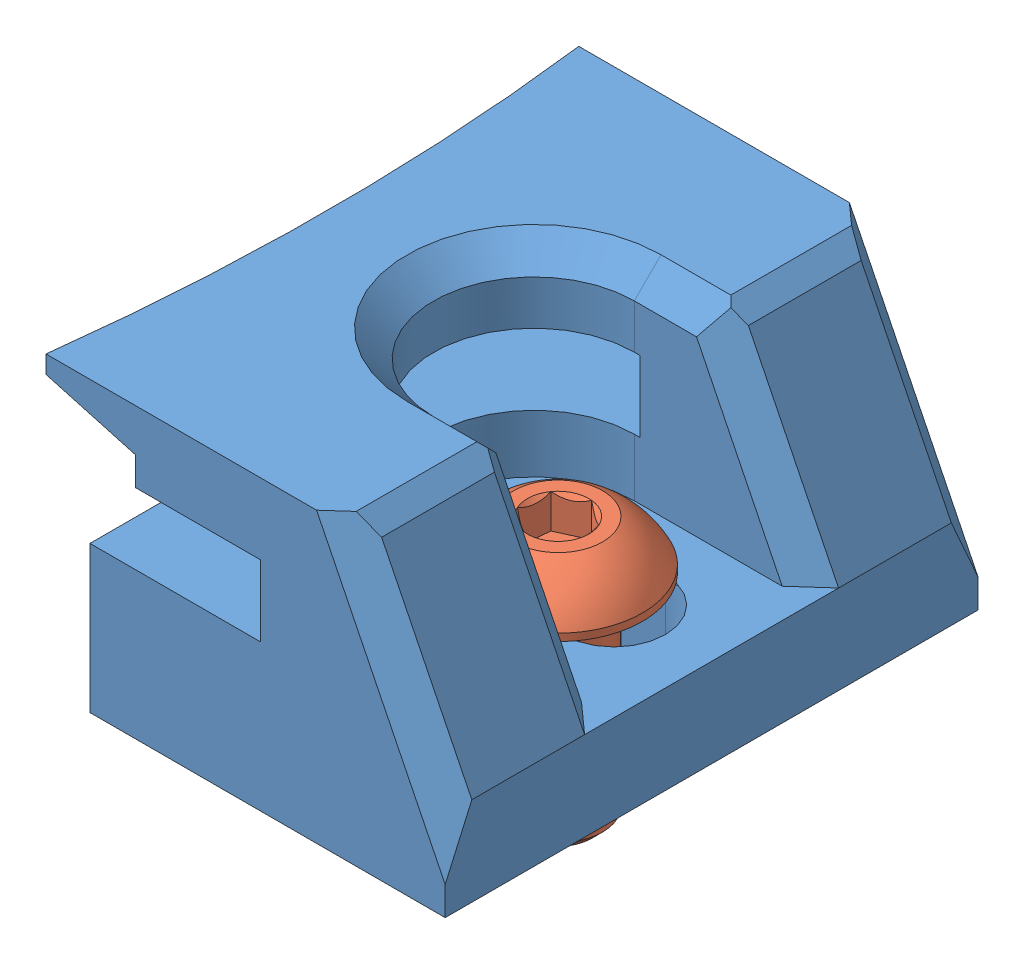
SolidWorks assembly Heated Bed Glass Clamps, configuration Default. Lengths in mm.
Overall size (22.48 23.25 30).
3 component instances, 3 part files, 8 mates.
Components (placement in the parent):
- Glass_clamp-1: Glass_clamp [Default] at origin size (22.48 16.25 30)
- M5 x 12mm -  Button Head Screw - SST (92095A210)-1: M5 x 12mm -  Button Head Screw - SST (92095A210) [92095A210] at (11.359 7.75 0) x (0.413548 0 0.910482) z (0 1 0) size (9.5 9.5 14.92)
- Tee Nut-1: Tee Nut [Default] at (11.359 -1.8 0) x (0 0 -1) z (0 -1 0) size (15 10 3)
Mates (geometry in assembly coordinates):
- Coincident1: coincident aligned: plane of Glass_clamp-1 through (0 0 0) normal (0 0 1); plane of assembly through (0 0 0) normal (0 0 1)
- Coincident2: coincident aligned: plane of Glass_clamp-1 through (0 0 0) normal (0 1 0); plane of assembly through (0 0 0) normal (0 1 0)
- Coincident3: coincident aligned: plane of Glass_clamp-1 through (0 0 0) normal (1 0 0); plane of assembly through (0 0 0) normal (1 0 0)
- Slot1: slot anti-aligned: cylinder of M5 x 12mm -  Button Head Screw - SST (92095A210)-1 through (11.359 -7 0) axis (0 -1 0) radius 2.5; cylinder of Glass_clamp-1 through (10 -11.8207 0) axis (0 1 0) radius 2.9; cylinder of Glass_clamp-1 through (14.5 -11.8207 0) axis (0 1 0) radius 2.9
- Coincident4: coincident anti-aligned: plane of Glass_clamp-1 through (0 5 0) normal (0 1 0); plane of M5 x 12mm -  Button Head Screw - SST (92095A210)-1 through (7.0342 5 1.9644) normal (0 -1 0)
- Concentric1: concentric aligned: cylinder of M5 x 12mm -  Button Head Screw - SST (92095A210)-1 through (11.359 -7 0) axis (0 -1 0) radius 2.5; cylinder of Tee Nut-1 through (11.359 -4.8 0) axis (0 -1 0) radius 2.1
- Parallel1: parallel aligned: plane of Glass_clamp-1 through (20 0 -15) normal (1 0 0); plane of Tee Nut-1 through (16.359 -3.4 3) normal (1 0 0)
- Distance1: distance = 1.8 mm anti-aligned: plane of Tee Nut-1 through (14.359 -1.8 -6) normal (0 1 0); plane of Glass_clamp-1 through (0 0 -15) normal (0 -1 0)
